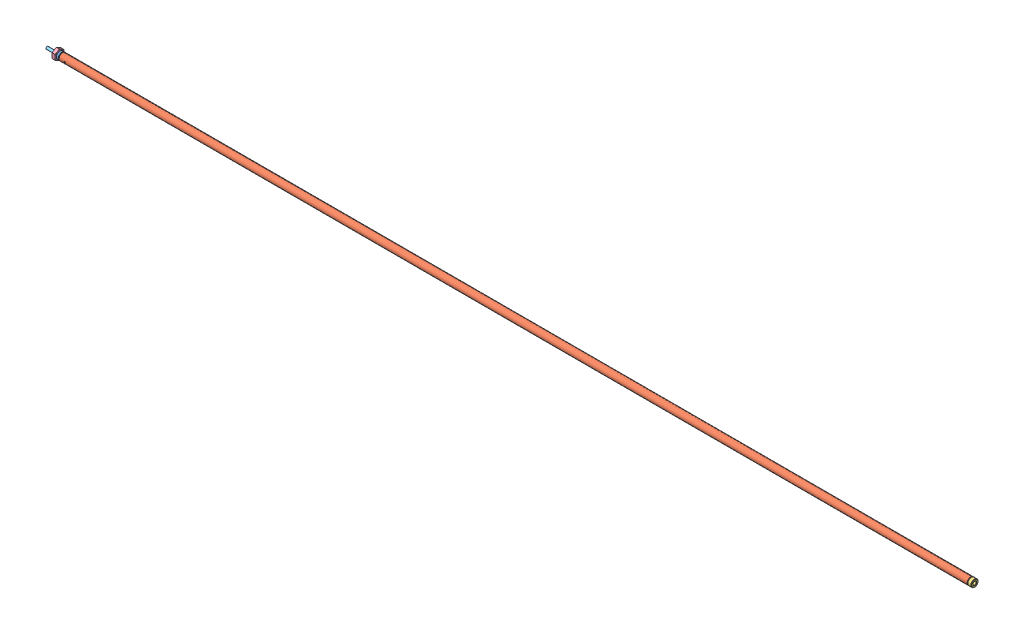
SolidWorks assembly Assem5, configuration Default. Lengths in mm.
Overall size (1181.1 12.9 11.18).
6 component instances, 6 part files, 14 mates.
Components (placement in the parent):
- 007300000_0_dummy-1: 007300000_0_dummy [Default] at origin
- 007000-0_rod_guide-1: 007000-0_rod_guide [Default] at origin size (15.88 9.12 9.12)
- 007-45_53652-1: 007-45_53652 [Default] at (9.9568 0 0) size (1157.59 9.12 9.12)
- 0070000_rear_head-1: 0070000_rear_head [Default] at (1163.1168 0 0) size (8.33 9.12 9.12)
- D-344-1: D-344 [Default] at (6.35 0 0) x (0 0 -1) z (1 0 0) size (11.18 12.9 4.06)
- 007300_rod-1: 007300_rod [Default] at origin size (1172.77 8.06 8.06)
Mates (geometry in assembly coordinates):
- Distance2: distance = 0 mm aligned: plane of 007000-0_rod_guide-1 through (0 0 0) normal (1 0 0); plane of 007300000_0_dummy-1 through (0 0 0) normal (1 0 0)
- Coincident1: coincident aligned: line of 007300000_0_dummy-1 through (80.9 0 0) axis (-1 0 0); line of 007000-0_rod_guide-1 through (80.9 0 0) axis (-1 0 0)
- Angle3: planar angle = 0 rad aligned: plane of 007000-0_rod_guide-1 through (0 0 0) normal (0 0 -1); plane of 007300000_0_dummy-1 through (0 0 0) normal (0 0 -1)
- Distance4: distance = 0 mm aligned: plane of 007-45_53652-1 through (9.9568 0 0) normal (1 0 0); plane of 007000-0_rod_guide-1 through (9.9568 0 0) normal (1 0 0)
- Coincident2: coincident aligned: line of 007000-0_rod_guide-1 through (80.9 0 0) axis (-1 0 0); line of 007-45_53652-1 through (90.8568 0 0) axis (-1 0 0)
- Angle6: planar angle = 0 rad aligned: plane of 007-45_53652-1 through (9.9568 0 0) normal (0 0 -1); plane of 007000-0_rod_guide-1 through (0 0 0) normal (0 0 -1)
- Distance6: distance = 0 mm aligned: plane of 0070000_rear_head-1 through (1166.5839 0 0) normal (1 0 0); plane of 007-45_53652-1 through (1166.5839 0 0) normal (1 0 0)
- Coincident3: coincident aligned: line of 007-45_53652-1 through (90.8568 0 0) axis (-1 0 0); line of 0070000_rear_head-1 through (1244.0168 0 0) axis (-1 0 0)
- Angle9: planar angle = 0 rad aligned: plane of 0070000_rear_head-1 through (1163.1168 0 0) normal (0 0 -1); plane of 007-45_53652-1 through (9.9568 0 0) normal (0 0 -1)
- Distance8: distance = 0 mm aligned: plane of D-344-1 through (6.35 0 0) normal (1 0 0); plane of 007000-0_rod_guide-1 through (6.35 0 0) normal (1 0 0)
- Coincident4: coincident aligned: line of 007000-0_rod_guide-1 through (80.9 0 0) axis (-1 0 0); line of D-344-1 through (87.25 0 0) axis (-1 0 0)
- Angle12: planar angle = 0 rad aligned: plane of D-344-1 through (6.35 0 0) normal (0 0 -1); plane of 007000-0_rod_guide-1 through (0 0 0) normal (0 0 -1)
- LimitDistance2: limit distance = 0 mm aligned: plane of 007300_rod-1 through (0 0 0) normal (1 0 0); plane of 007000-0_rod_guide-1 through (0 0 0) normal (1 0 0)
- Coincident5: coincident aligned: line of 007000-0_rod_guide-1 through (80.9 0 0) axis (-1 0 0); line of 007300_rod-1 through (80.9 0 0) axis (-1 0 0)
